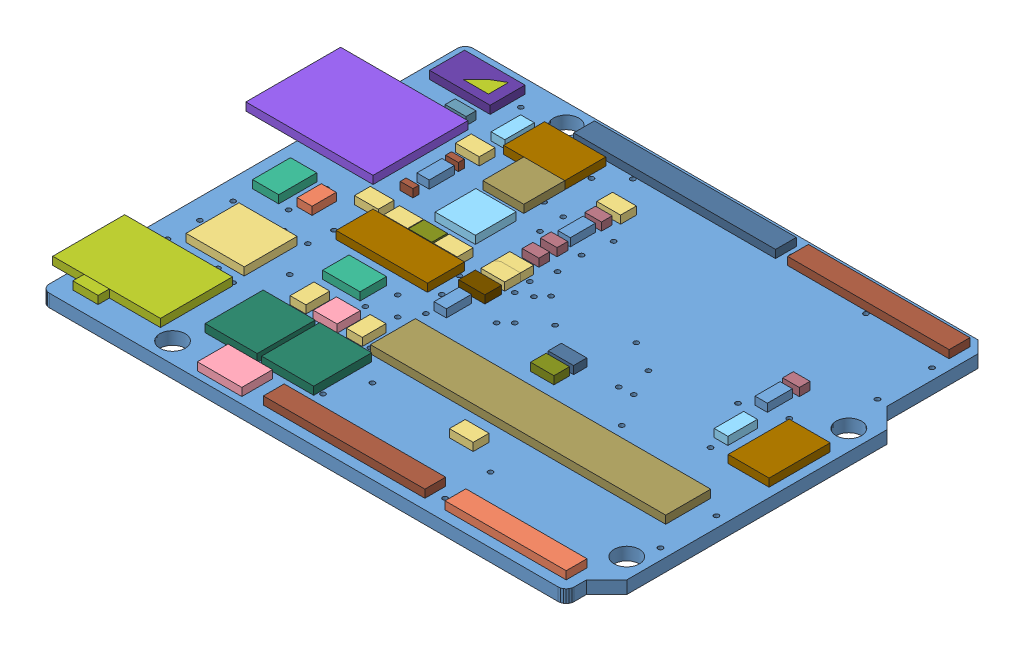
SolidWorks assembly arduino_uno_rev302th, configuration Default. Lengths in mm.
Overall size (75.05 3.6 53.34).
53 component instances, 30 part files, 0 mates.
Components (placement in the parent):
- arduino_uno_rev302th-1: arduino_uno_rev302th [Default] x (1 0 0) z (0 1 0) size (68.58 53.34 1.6)
- 1X06_1X06-1: 1X06_1X06 [Default] at (57.15 1.6 -2.54) x (1 0 0) z (0 1 0) size (15.24 2.62 1)
- C0603ROUND_C0603ROUND-1: C0603ROUND_C0603ROUND [Default] at (18.415 1.6 -15.367) x (0 0 1) z (0 1 0) size (3 1.99 1)
- C0603ROUND_C0603ROUND-2: C0603ROUND_C0603ROUND [Default] at (12.065 1.6 -29.845) x (-1 0 0) z (0 1 0) size (3 1.99 1)
- C0603ROUND_C0603ROUND-3: C0603ROUND_C0603ROUND [Default] at (25.527 1.6 -15.367) x (0 0 -1) z (0 1 0) size (3 1.99 1)
- C0603ROUND_C0603ROUND-4: C0603ROUND_C0603ROUND [Default] at (27.94 1.6 -44.45) x (-1 0 0) z (0 1 0) size (3 1.99 1)
- C0603ROUND_C0603ROUND-5: C0603ROUND_C0603ROUND [Default] at (27.94 1.6 -29.845) x (1 0 0) z (0 1 0) size (3 1.99 1)
- C0603ROUND_C0603ROUND-6: C0603ROUND_C0603ROUND [Default] at (43.434 1.6 -10.414) x (-1 0 0) z (0 1 0) size (3 1.99 1)
- C0603ROUND_C0603ROUND-7: C0603ROUND_C0603ROUND [Default] at (27.94 1.6 -31.496) x (1 0 0) z (0 1 0) size (3 1.99 1)
- C0603ROUND_C0603ROUND-8: C0603ROUND_C0603ROUND [Default] at (12.7 1.6 -41.91) x (-1 0 0) z (0 1 0) size (3 1.99 1)
- C0603ROUND_C0603ROUND-9: C0603ROUND_C0603ROUND [Default] at (16.002 1.6 -29.591) x (-1 0 0) z (0 1 0) size (3 1.99 1)
- C0603ROUND_C0603ROUND-10: C0603ROUND_C0603ROUND [Default] at (22.225 1.6 -29.591) x (1 0 0) z (0 1 0) size (3 1.99 1)
- SMB_M7-1: SMB_M7 [Default] at (21.59 1.6 -2.794) x (-1 0 0) z (0 1 0) size (5.59 3.86 1)
- MINIMELF_CD1206S01575-1: MINIMELF_CD1206S01575 [Default] at (59.436 1.6 -27.94) x (0 0 1) z (0 1 0) size (3.71 1.73 1)
- MINIMELF_CD1206S01575-2: MINIMELF_CD1206S01575 [Default] at (13.081 1.6 -46.228) x (0 0 -1) z (0 1 0) size (3.71 1.73 1)
- L1812_L1812-1: L1812_L1812 [Default] at (4.064 1.6 -26.543) x (0 0 -1) z (0 1 0) size (4.79 3.3 1)
- FIDUCIAMOUNT_FIDUCIAMOUNT-1: FIDUCIAMOUNT_FIDUCIAMOUNT [Default] at (6.35 1.6 -49.911) x (1 0 0) z (0 1 0) size (3.18 3.18 1)
- FIDUCIAMOUNT_FIDUCIAMOUNT-2: FIDUCIAMOUNT_FIDUCIAMOUNT [Default] at (53.84 1.6 -16.741) x (1 0 0) z (0 1 0) size (3.18 3.18 1)
- FIDUCIAMOUNT_FIDUCIAMOUNT-3: FIDUCIAMOUNT_FIDUCIAMOUNT [Default] at (3.73 1.6 -3.41) x (1 0 0) z (0 1 0) size (3.18 3.18 1)
- SJ_GROUND_SJ-1: SJ_GROUND_SJ [Default] at (11.43 0 -40.64) x (-1 0 0) z (0 -1 0) size (3.3 2.11 1)
- 2X03_2X03-1: 2X03_2X03 [Default] at (64.897 1.6 -27.94) x (0 0 1) z (0 1 0) size (7.7 5.16 1)
- 2X03_2X03-2: 2X03_2X03 [Default] at (18.288 1.6 -46.228) x (-1 0 0) z (0 1 0) size (7.7 5.16 1)
- 1X10_1X10-1: 1X10_1X10 [Default] at (30.226 1.6 -50.8) x (-1 0 0) z (0 1 0) size (25.4 2.62 1)
- 1X08_1X08-1: 1X08_1X08 [Default] at (54.61 1.6 -50.8) x (-1 0 0) z (0 1 0) size (20.32 2.62 1)
- 1X08_1X08-2: 1X08_1X08 [Default] at (36.83 1.6 -2.54) x (1 0 0) z (0 1 0) size (20.32 2.62 1)
- 2X02_2X02-1: 2X02_2X02 [Default] at (19.558 1.6 -41.148) x (0 0 -1) z (0 1 0) size (5.16 5.16 1)
- CHIPLED0805_CHIPLED0805-1: CHIPLED0805_CHIPLED0805 [Default] at (27.94 1.6 -42.164) x (0 0 1) z (0 1 0) size (1.35 2.1 1)
- CHIPLED0805_CHIPLED0805-2: CHIPLED0805_CHIPLED0805 [Default] at (58.42 1.6 -36.576) x (0 0 1) z (0 1 0) size (1.35 2.1 1)
- CHIPLED0805_CHIPLED0805-3: CHIPLED0805_CHIPLED0805 [Default] at (27.94 1.6 -34.29) x (0 0 -1) z (0 1 0) size (1.35 2.1 1)
- CHIPLED0805_CHIPLED0805-4: CHIPLED0805_CHIPLED0805 [Default] at (27.94 1.6 -36.576) x (0 0 -1) z (0 1 0) size (1.35 2.1 1)
- 0805_BLM21-1: 0805_BLM21 [Default] at (7.62 1.6 -45.085) x (-1 0 0) z (0 1 0) size (2.63 1.25 1)
- PANASONIC_D_PANASONIC_D-1: PANASONIC_D_PANASONIC_D [Default] at (25.527 1.6 -9.144) x (0 0 -1) z (0 1 0) size (7.3 6.55 1)
- PANASONIC_D_PANASONIC_D-2: PANASONIC_D_PANASONIC_D [Default] at (18.415 1.6 -9.144) x (0 0 -1) z (0 1 0) size (7.3 6.55 1)
- R0603ROUND_R0603ROUND-1: R0603ROUND_R0603ROUND [Default] at (19.05 1.6 -29.591) x (1 0 0) z (0 1 0) size (2.95 1.97 1)
- R0603ROUND_R0603ROUND-2: R0603ROUND_R0603ROUND [Default] at (41.275 1.6 -22.733) x (-1 0 0) z (0 1 0) size (2.95 1.97 1)
- TS42_TS42-1: TS42_TS42 [Default] at (6.35 1.6 -49.403) x (1 0 0) z (0 1 0) size (7.61 4.4 1)
- SJ_RESETEN_SJ-1: SJ_RESETEN_SJ [Default] at (27.94 1.6 -27.305) x (1 0 0) z (0 1 0) size (3.3 2.11 1)
- CAY16_CAY16-1: CAY16_CAY16 [Default] at (27.94 1.6 -23.876) x (0 0 -1) z (0 1 0) size (3.15 1.55 1)
- CAY16_CAY16-2: CAY16_CAY16 [Default] at (27.94 1.6 -39.37) x (0 0 1) z (0 1 0) size (3.15 1.55 1)
- CAY16_CAY16-3: CAY16_CAY16 [Default] at (12.827 1.6 -36.83) x (0 0 -1) z (0 1 0) size (3.15 1.55 1)
- CAY16_CAY16-4: CAY16_CAY16 [Default] at (58.42 1.6 -33.782) x (0 0 -1) z (0 1 0) size (3.15 1.55 1)
- SOT23_FDN340P-1: SOT23_FDN340P [Default] at (8.128 1.6 -26.543) x (0 0 1) z (0 1 0) size (3.05 1.88 1)
- SOT223_NCP1117ST50T3G-1: SOT223_NCP1117ST50T3G [Default] at (7.747 1.6 -17.399) x (0 0 -1) z (0 1 0) size (6.65 7.32 1)
- SOT23DBV_SOT23DBV-1: SOT23DBV_SOT23DBV [Default] at (21.971 1.6 -15.24) x (0 0 1) z (0 1 0) size (2.92 3 1)
- MLF32_MLF32-1: MLF32_MLF32 [Default] at (19.939 1.6 -34.671) x (0 0 -1) z (0 1 0) size (5.13 5.06 1)
- MSOP08_LMV358IDGKR-1: MSOP08_LMV358IDGKR [Default] at (19.05 1.6 -20.32) x (0 0 -1) z (0 1 0) size (3.33 4.71 1)
- POWERSUPPLY_DC21MM_POWERSUPPLY_DC21MM-1: POWERSUPPLY_DC21MM_POWERSUPPLY_DC21MM [Default] at (5.334 1.6 -8.382) x (0 0 -1) z (0 1 0) size (9.06 13.55 1)
- PN61729_PN61729-1: PN61729_PN61729 [Default] at (3.81 1.6 -38.1) x (0 0 1) z (0 1 0) size (11.93 16 1)
- QS_QS-1: QS_QS [Default] at (18.923 1.6 -26.162) x (-1 0 0) z (0 1 0) size (11.51 4.65 1)
- RESONATOR_RESONATOR-1: RESONATOR_RESONATOR [Default] at (41.275 1.6 -24.892) x (1 0 0) z (0 1 0) size (3.2 1.66 1)
- CT_CN0603_CG0603MLC05E-1: CT_CN0603_CG0603MLC05E [Default] at (12.7 1.6 -39.37) x (-1 0 0) z (0 1 0) size (1.6 0.75 1)
- CT_CN0603_CG0603MLC05E-2: CT_CN0603_CG0603MLC05E [Default] at (12.7 1.6 -33.655) x (-1 0 0) z (0 1 0) size (1.6 0.75 1)
- DIL283_DIL283-1: DIL283_DIL283 [Default] at (46.355 1.6 -16.383) x (-1 0 0) z (0 1 0) size (37.16 5.66 1)
